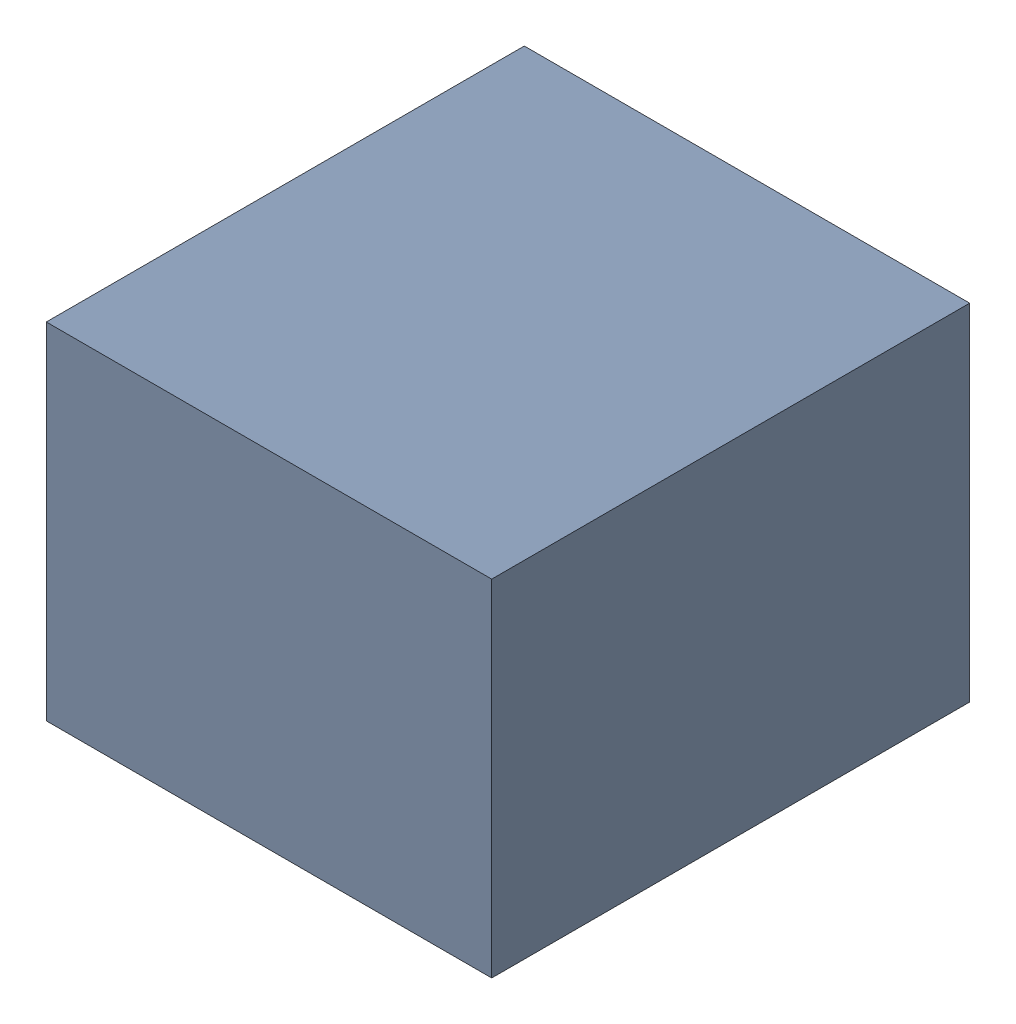
SolidWorks assembly R401PCB, configuration Default. Lengths in mm.
Overall size (4.1 3.18 4.4).
2 component instances, 1 part files, 0 mates.
Components (placement in the parent):
- 846484920-1: 846484920 [Default] at (84.7 122.0001 0) size (4.1 3.18 4.4)
  - Extruded_46-1: Extruded_46 [Default] at origin size (4.1 3.18 4.4)
